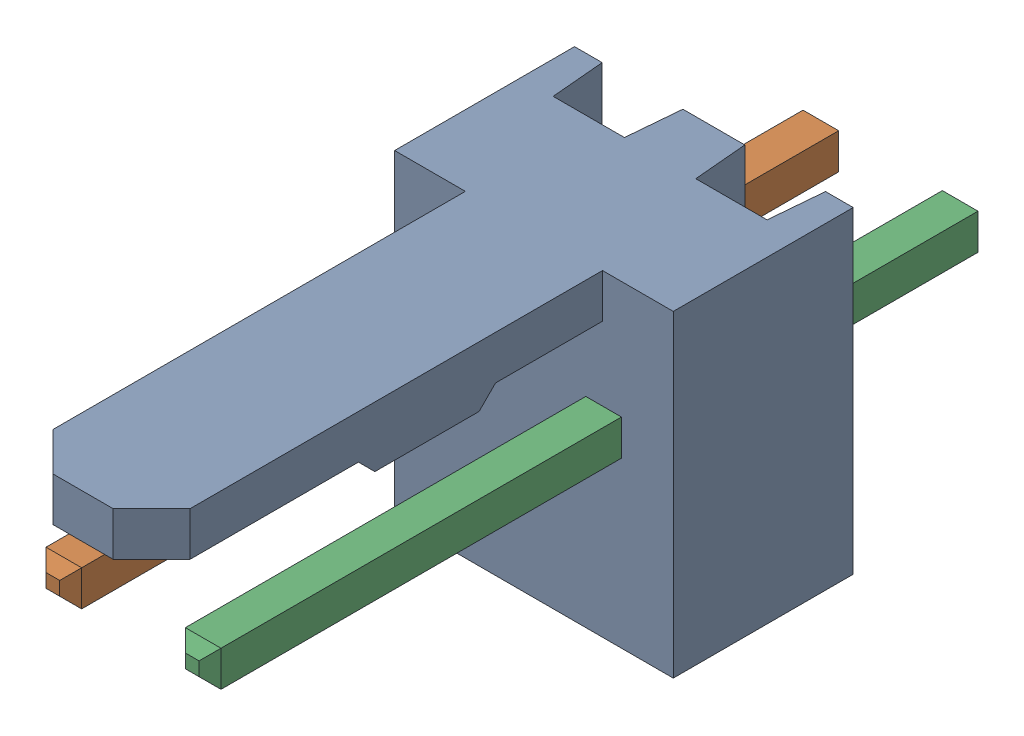
SolidWorks assembly Molex PCB 2 pin v2_6, configuration Default. Lengths in mm.
Overall size (5.08 5.79 14.92).
3 component instances, 2 part files, 0 mates.
Components (placement in the parent):
- BASE9710016_1-1: BASE9710016_1 [Default] at (2.54 2.895 -8.22) size (5.08 5.79 11.5)
- PINO9710016_1-1: PINO9710016_1 [Default] at (1.27 3.325 -0.72) size (0.65 0.65 14.2)
- PINO9710016_1-2: PINO9710016_1 [Default] at (3.81 3.325 -0.72) size (0.65 0.65 14.2)
